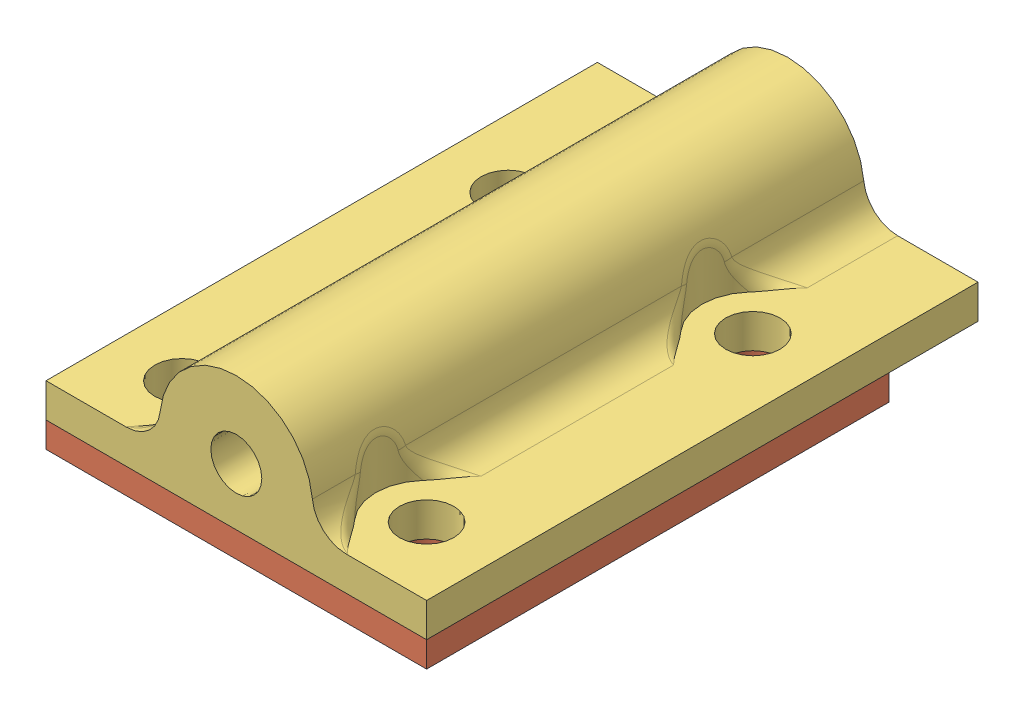
SolidWorks assembly power_glove_sensor, configuration Default. Lengths in mm.
Overall size (22.4 10.18 32.59).
5 component instances, 4 part files, 16 mates.
Components (placement in the parent):
- leaf_spring-1: leaf_spring [Default] at (-1.7 0 0) size (2.7 2.5 12)
- leaf_spring-2: leaf_spring [Default] at (1.7 0 0) size (2.7 2.5 12)
- powerglove_board-1: powerglove_board [Default] at origin size (22.4 1.5 27.2)
- power_glove_housing-1: power_glove_housing [Default] at origin size (22.4 8.68 32.59)
- switch_tube-1: switch_tube [Default] at (0 3.7987 -9.85) size (4.76 4.76 12.55)
Mates (geometry in assembly coordinates):
- Coincident1: coincident aligned: plane of leaf_spring-1 through (-1.7 0 0) normal (0 1 0); plane of assembly through (0 0 0) normal (0 1 0)
- Coincident2: coincident aligned: plane of leaf_spring-2 through (1.7 0 0) normal (0 1 0); plane of assembly through (0 0 0) normal (0 1 0)
- Coincident3: coincident aligned: plane of leaf_spring-1 through (-1.7 0 0) normal (0 0 1); plane of assembly through (0 0 0) normal (0 0 1)
- Coincident4: coincident aligned: plane of leaf_spring-2 through (1.7 0 0) normal (0 0 1); plane of assembly through (0 0 0) normal (0 0 1)
- Distance1: distance = 0.2 mm: line of assembly; line of leaf_spring-1 through (-0.2 0 -6.2) axis (0 0 1)
- Distance2: distance = 0.2 mm: line of leaf_spring-2 through (0.2 0 -6.2) axis (0 0 1); line of assembly
- Coincident7: coincident aligned: plane of powerglove_board-1 through (0 0 0) normal (0 1 0); plane of assembly through (0 0 0) normal (0 1 0)
- Coincident8: coincident aligned: plane of powerglove_board-1 through (0 0 0) normal (1 0 0); plane of assembly through (0 0 0) normal (1 0 0)
- Coincident9: coincident aligned: plane of powerglove_board-1 through (0 0 0) normal (0 0 1); plane of assembly through (0 0 0) normal (0 0 1)
- Coincident10: coincident aligned: plane of power_glove_housing-1 through (0 0 0) normal (0 1 0); plane of assembly through (0 0 0) normal (0 1 0)
- Coincident11: coincident aligned: plane of power_glove_housing-1 through (0 0 0) normal (1 0 0); plane of assembly through (0 0 0) normal (1 0 0)
- Coincident12: coincident aligned: plane of power_glove_housing-1 through (0 0 0) normal (0 0 1); plane of assembly through (0 0 0) normal (0 0 1)
- Coincident13: coincident aligned: plane of switch_tube-1 through (0 3.7987 -9.85) normal (1 0 0); plane of assembly through (0 0 0) normal (1 0 0)
- Coincident14: coincident: plane of switch_tube-1 through (0 3.7987 -9.85) normal (0 1 0); line of assembly
- Distance3: distance = 7 mm: plane of switch_tube-1 through (0 3.7987 -9.85) normal (0 0 1); point of power_glove_housing-1
- Parallel1: parallel aligned: plane of switch_tube-1 through (0 3.7987 -9.85) normal (0 1 0); plane of assembly through (0 0 0) normal (0 1 0)
